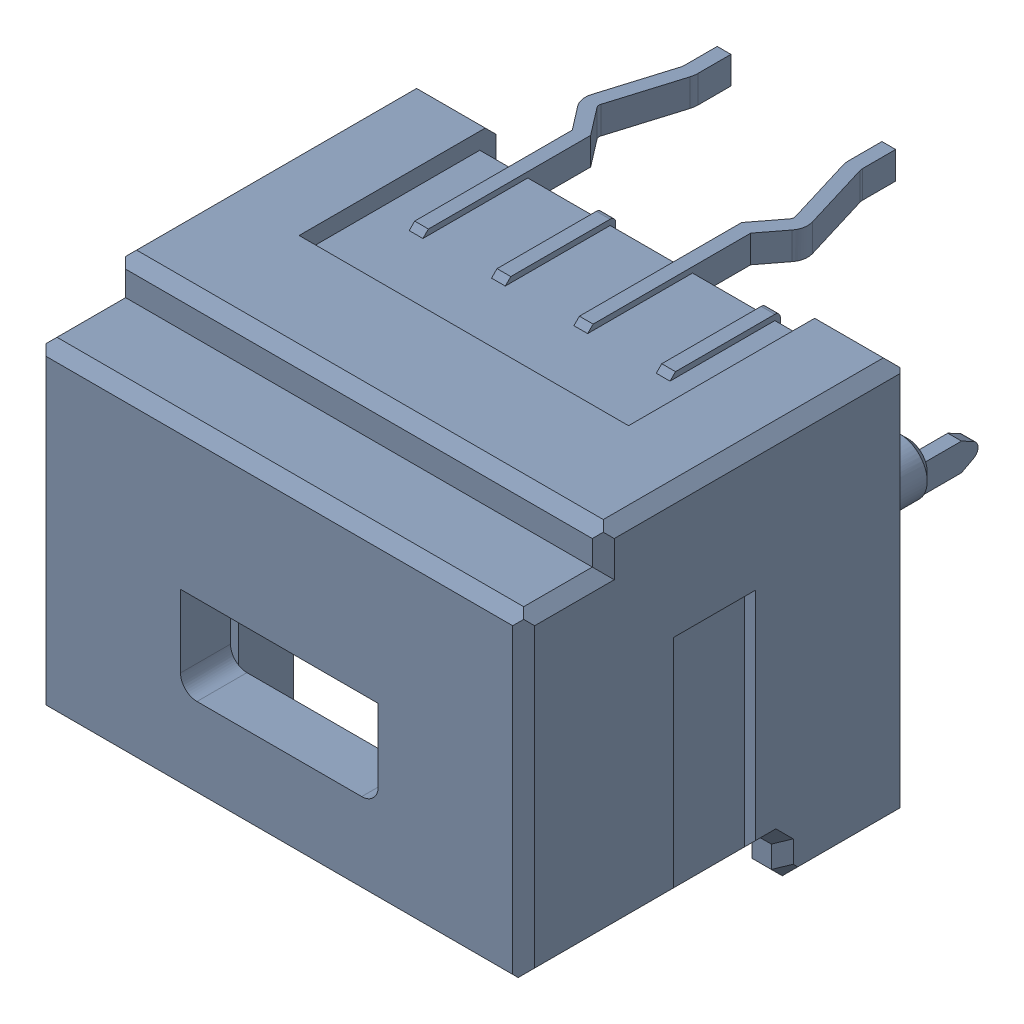
SolidWorks assembly J1, configuration Default. Lengths in mm.
Overall size (8.9 7.25 10.35).
2 component instances, 1 part files, 0 mates.
Components (placement in the parent):
- 5031750400-1: 5031750400 [Default] at (5.1951 -6.2699 4.3628) x (-1 0 0) z (0 1 0) size (8.9 10.35 7.25)
  - Open CASCADE STEP translator 7.5 1.20.1.1-1: Open CASCADE STEP translator 7.5 1.20.1.1 [Default] at origin size (8.9 10.35 7.25)
